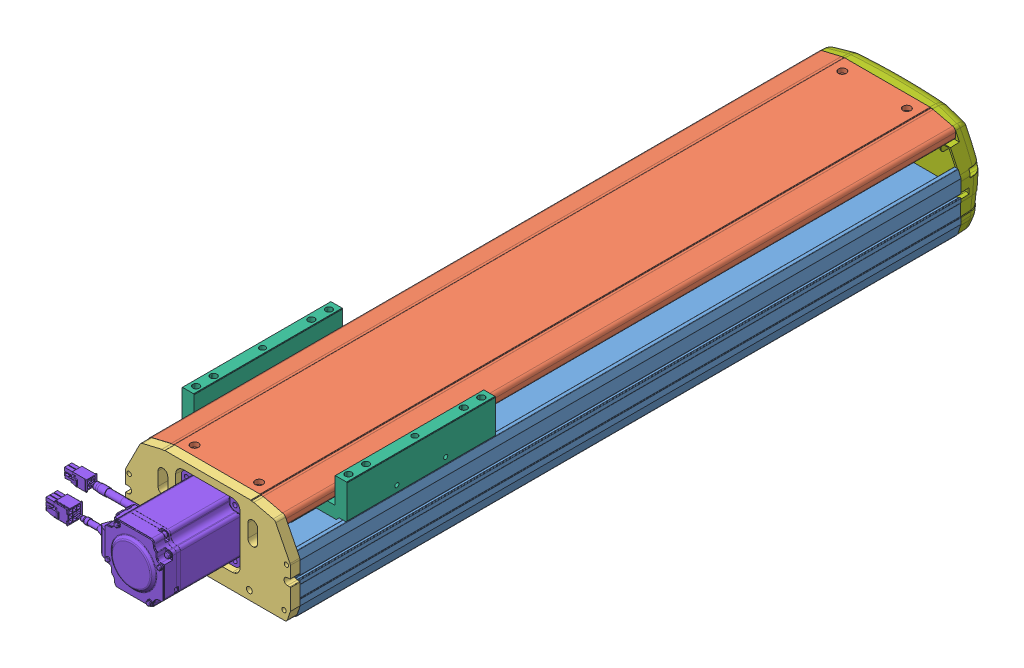
SolidWorks assembly S17-BC-400W, configuration 默认. Lengths in mm.
Overall size (204.48 97.04 794.72).
10 component instances, 8 part files, 37 mates.
Components (placement in the parent):
- S17-BC底座^S17-BC-400W-1: S17-BC底座^S17-BC-400W [默认] at origin size (170 59.5 693.5) (virtual)
- S17-BC上盖^S17-BC-400W-2: S17-BC上盖^S17-BC-400W [默认] at (0 90.5 7.5) size (140 15.5 686) (virtual)
- S17-BC-P75电机板^S17-BC-400W-1: S17-BC-P75电机板^S17-BC-400W [默认] at (-2427.4256 -1270.1968 693.5) size (169 89.5 10) (virtual)
- EE-SX672 传感器^S17-BC-400W-1: EE-SX672 传感器^S17-BC-400W [默认] at (-91.7485 41.1 553.8) x (-1 0 0) z (0 0 1) size (13.5 27.4 26.1) (virtual)
- EE-SX672 传感器^S17-BC-400W-2: EE-SX672 传感器^S17-BC-400W [默认] at (-91.7485 41.1 579.9) x (-1 0 0) z (0 0 1) size (13.5 27.4 26.1) (virtual)
- EE-SX672 传感器^S17-BC-400W-3: EE-SX672 传感器^S17-BC-400W [默认] at (-91.7485 41.1 108) x (-1 0 0) z (0 0 1) size (13.5 27.4 26.1) (virtual)
- S17-BC 感应片(外置)^S17-BC-400W-1: S17-BC 感应片(外置)^S17-BC-400W [默认] at (-84.5 76 534) x (-1 0 0) z (0 0 -1) size (8 30 70) (virtual)
- S17-BC丝杆螺母连接座^S17-BC-400W-1: S17-BC丝杆螺母连接座^S17-BC-400W [Default] at (0 97 569) size (169 71 152) (virtual)
- 复件 S17塑胶端盖^S17-BC-400W-1: 复件 S17塑胶端盖^S17-BC-400W [Default] at (0 -0.0852 -13) x (-1 0 0) z (0 0 -1) size (170.72 91.84 30.22) (virtual)
- 复件 松下400W电机MHMF042L1U22^S17-BC-400W-1: 复件 松下400W电机MHMF042L1U22^S17-BC-400W [默认] at (-0.0015 49.75 693.5) x (0 0 -1) z (0 1 0) size (118 149.2 60) (virtual)
Mates (geometry in assembly coordinates):
- 重合139: coincident: plane of S17-BC底座^S17-BC-400W-1 through (0 0 693.5) normal (0 0 1); plane of S17-BC-P75电机板^S17-BC-400W-1 through (84.4985 41 693.5) normal (0 0 -1)
- 重合141: coincident: plane of S17-BC底座^S17-BC-400W-1 through (84.9985 0 693.5) normal (1 0 0); plane of S17-BC-P75电机板^S17-BC-400W-1 through (84.9985 41 703.5) normal (1 0 0)
- 距离10: distance = 97 mm: plane of S17-BC丝杆螺母连接座^S17-BC-400W-1 through (72.5 97 645) normal (0 1 0); plane of S17-BC底座^S17-BC-400W-1 through (0 0 693.5) normal (0 -1 0)
- 距离11: distance = 90.5 mm: plane of S17-BC上盖^S17-BC-400W-2 through (-43.7927 90.5 693.5) normal (0 1 0); plane of S17-BC底座^S17-BC-400W-1 through (0 0 693.5) normal (0 -1 0)
- 重合153: coincident: plane of S17-BC底座^S17-BC-400W-1 through (0 0 0) normal (1 0 0); plane of S17-BC上盖^S17-BC-400W-2 through (0 90.5 7.5) normal (1 0 0)
- 重合156: coincident: plane of S17-BC底座^S17-BC-400W-1 through (0 0 0) normal (1 0 0); plane of S17-BC丝杆螺母连接座^S17-BC-400W-1 through (0 97 569) normal (1 0 0)
- 距离14: distance = 1 mm: plane of S17-BC-P75电机板^S17-BC-400W-1 through (-78.1455 1 703.5) normal (0 -1 0); plane of S17-BC底座^S17-BC-400W-1 through (0 0 693.5) normal (0 -1 0)
- 重合157: coincident: plane of EE-SX672 传感器^S17-BC-400W-1 through (-84.9985 52.2 560.1) normal (1 0 0); plane of EE-SX672 传感器^S17-BC-400W-3 through (-84.9985 52.2 114.3) normal (1 0 0)
- 重合158: coincident: plane of EE-SX672 传感器^S17-BC-400W-1 through (-84.9985 52.2 560.1) normal (1 0 0); plane of EE-SX672 传感器^S17-BC-400W-2 through (-84.9985 52.2 586.2) normal (1 0 0)
- 重合159: coincident: plane of EE-SX672 传感器^S17-BC-400W-1 through (-84.9985 52.2 560.1) normal (0 1 0); plane of EE-SX672 传感器^S17-BC-400W-3 through (-84.9985 52.2 114.3) normal (0 1 0)
- 重合160: coincident: plane of EE-SX672 传感器^S17-BC-400W-1 through (-84.9985 52.2 560.1) normal (0 1 0); plane of EE-SX672 传感器^S17-BC-400W-2 through (-84.9985 52.2 586.2) normal (0 1 0)
- 距离20: distance = 30 mm: plane of S17-BC底座^S17-BC-400W-1 through (0 0 693.5) normal (0 -1 0); plane of EE-SX672 传感器^S17-BC-400W-2 through (-84.9985 30 586.2) normal (0 -1 0)
- 同心109: concentric: cylinder of S17-BC 感应片(外置)^S17-BC-400W-1 through (-84.5 69 593.3) axis (1 0 0) radius 2.8; cylinder of S17-BC丝杆螺母连接座^S17-BC-400W-1 through (-84.5 69 593.3) axis (-1 0 0) radius 2.1
- 同心111: concentric: cylinder of S17-BC 感应片(外置)^S17-BC-400W-1 through (-84.5 69 543.3) axis (1 0 0) radius 2.8; cylinder of S17-BC丝杆螺母连接座^S17-BC-400W-1 through (-84.5 69 543.3) axis (-1 0 0) radius 2.1
- 重合163: coincident: plane of S17-BC丝杆螺母连接座^S17-BC-400W-1 through (-84.5 62.7074 645) normal (-1 0 0); plane of S17-BC 感应片(外置)^S17-BC-400W-1 through (-84.5 76 534) normal (1 0 0)
- 距离21: distance = 108 mm: plane of EE-SX672 传感器^S17-BC-400W-3 through (-98.4985 30 108) normal (0 0 -1); plane of S17-BC底座^S17-BC-400W-1 through (0 0 0) normal (0 0 -1)
- 重合168: coincident: plane of S17-BC底座^S17-BC-400W-1 through (-84.9985 0 693.5) normal (-1 0 0); plane of EE-SX672 传感器^S17-BC-400W-2 through (-84.9985 52.2 586.2) normal (1 0 0)
- 重合169: coincident: plane of EE-SX672 传感器^S17-BC-400W-1 through (-87.9985 33.2 570) normal (0 0 1); plane of EE-SX672 传感器^S17-BC-400W-2 through (-87.9985 33.2 570) normal (0 0 -1)
- 距离22: distance = 108 mm: plane of EE-SX672 传感器^S17-BC-400W-2 through (-98.4985 30 586.2) normal (0 0 1); plane of S17-BC底座^S17-BC-400W-1 through (0 0 693.5) normal (0 0 1)
- 重合170: coincident: plane of S17-BC底座^S17-BC-400W-1 through (0 0 0) normal (0 0 1); plane of assembly through (0 0 0) normal (0 0 1)
- 重合171: coincident: plane of S17-BC底座^S17-BC-400W-1 through (0 0 0) normal (0 1 0); plane of assembly through (0 0 0) normal (0 1 0)
- 重合172: coincident: plane of S17-BC底座^S17-BC-400W-1 through (0 0 0) normal (1 0 0); plane of assembly through (0 0 0) normal (1 0 0)
- 重合176: coincident: plane of S17-BC上盖^S17-BC-400W-2 through (68.2998 76.7 693.5) normal (0 0 1); plane of S17-BC-P75电机板^S17-BC-400W-1 through (84.4985 41 693.5) normal (0 0 -1)
- 重合177: coincident: plane of S17-BC底座^S17-BC-400W-1 through (98.2603 59.4999 17) normal (0 0 -1); plane of 复件 S17塑胶端盖^S17-BC-400W-1 through (0 -0.0852 17) normal (0 0 1)
- 重合178: coincident: line of S17-BC上盖^S17-BC-400W-2 through (43.7927 90.5 7.5) axis (-1 0 0); line of 复件 S17塑胶端盖^S17-BC-400W-1 through (43.4408 90.5 7.5) axis (-1 0 0)
- 重合179: coincident: line of S17-BC底座^S17-BC-400W-1 through (79.4985 35.3956 17) axis (0 1 0); line of 复件 S17塑胶端盖^S17-BC-400W-1 through (79.4985 38.7648 17) axis (0 -1 0)
- 重合180: coincident: plane of S17-BC-P75电机板^S17-BC-400W-1 through (-0.0015 54 698.5) normal (0 0 1); plane of 复件 松下400W电机MHMF042L1U22^S17-BC-400W-1 through (-24.5015 49.75 698.5) normal (0 0 -1)
- 宽度1: width: plane of S17-BC-P75电机板^S17-BC-400W-1 through (43.6909 90.5 703.5) normal (0 1 0); plane of S17-BC-P75电机板^S17-BC-400W-1 through (-78.7457 1 703.5) normal (0 -1 0); plane of 复件 松下400W电机MHMF042L1U22^S17-BC-400W-1; plane of 复件 松下400W电机MHMF042L1U22^S17-BC-400W-1
- 宽度2: width: plane of S17-BC-P75电机板^S17-BC-400W-1; plane of S17-BC-P75电机板^S17-BC-400W-1; plane of 复件 松下400W电机MHMF042L1U22^S17-BC-400W-1; plane of 复件 松下400W电机MHMF042L1U22^S17-BC-400W-1
- 宽度3: width: plane of S17-BC 感应片(外置)^S17-BC-400W-1 through (-85.3 63 561.8) normal (0 0 -1); plane of S17-BC 感应片(外置)^S17-BC-400W-1 through (-85.3 46 576.8) normal (0 0 1); plane of EE-SX672 传感器^S17-BC-400W-1 through (-98.4985 30 559.4) normal (0 0 1); plane of EE-SX672 传感器^S17-BC-400W-2 through (-98.4985 30 579.2) normal (0 0 -1)
- 距离23: distance = 85 mm: cylinder of 复件 松下400W电机MHMF042L1U22^S17-BC-400W-1 through (-0.0015 49.75 663.5) axis (0 0 1) radius 7; plane of S17-BC底座^S17-BC-400W-1 through (84.9985 0 693.5) normal (1 0 0)
- 距离24: distance = 49.75 mm: cylinder of 复件 松下400W电机MHMF042L1U22^S17-BC-400W-1 through (-0.0015 49.75 663.5) axis (0 0 1) radius 7; plane of S17-BC底座^S17-BC-400W-1 through (0 0 693.5) normal (0 -1 0)
- 平行1: parallel: plane of S17-BC-P75电机板^S17-BC-400W-1 through (44.2912 90.5 703.5) normal (0 1 0); plane of 复件 松下400W电机MHMF042L1U22^S17-BC-400W-1 through (-25.0015 79.75 765) normal (0 1 0)
- 距离25: distance = 3.5 mm: plane of 复件 松下400W电机MHMF042L1U22^S17-BC-400W-1 through (-0.0015 49.75 700) normal (0 0 1); plane of S17-BC-P75电机板^S17-BC-400W-1 through (84.4985 41 703.5) normal (0 0 1)
- 距离26: distance = 134.5 mm: plane of S17-BC-P75电机板^S17-BC-400W-1 through (84.4985 41 703.5) normal (0 0 1); cylinder of S17-BC丝杆螺母连接座^S17-BC-400W-1 through (78 97 569) axis (0 1 0) radius 3
- 同心112: concentric: circle of S17-BC 感应片(外置)^S17-BC-400W-1; circle of S17-BC丝杆螺母连接座^S17-BC-400W-1
- 宽度4: width: plane of EE-SX672 传感器^S17-BC-400W-2 through (-98.4985 30 579.9) normal (0 0 -1); plane of EE-SX672 传感器^S17-BC-400W-1 through (-98.4985 30 560.1) normal (0 0 1); plane of S17-BC 感应片(外置)^S17-BC-400W-1 through (-85.3 46 577.5) normal (0 0 1); plane of S17-BC 感应片(外置)^S17-BC-400W-1 through (-85.3 63 562.5) normal (0 0 -1)
